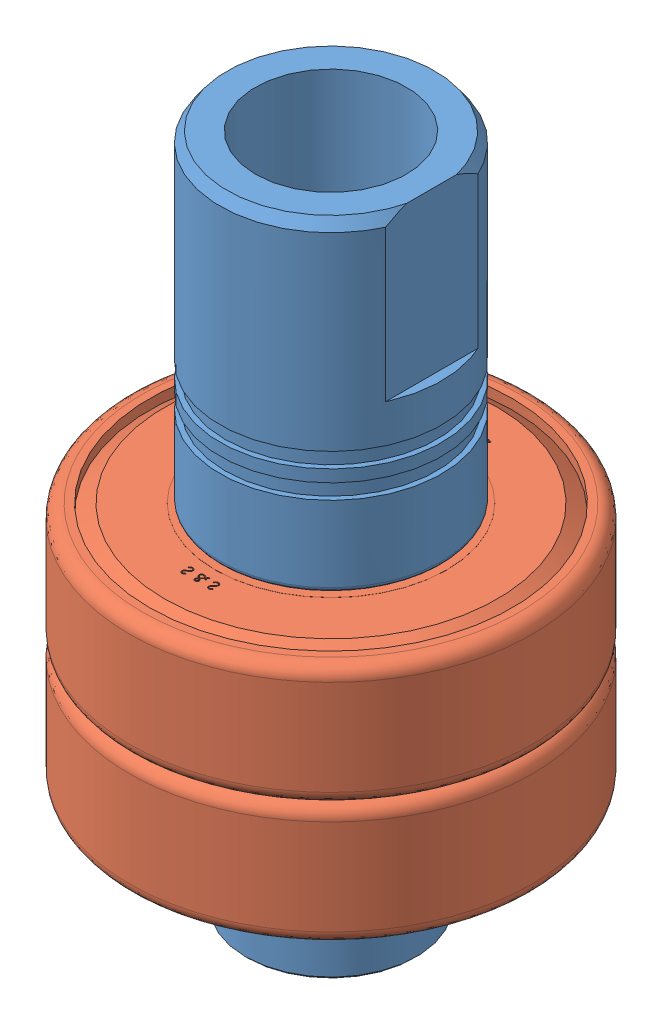
SolidWorks assembly Part5, configuration Default. Lengths in mm.
Overall size (54.35 67 54.35).
3 component instances, 2 part files, 4 mates.
Components (placement in the parent):
- Part5I-1: Part5I [Default] at (-13.2455 -26.8007 2.4381) size (22 67 22)
- Part5II-1: Part5II [Default] at (-13.2455 -3.8107 2.4381) size (40 12.01 40)
- Part5II-2: Part5II [Default] at (-13.2455 -3.8107 2.4381) x (0.483218 0 0.8755) z (0.8755 0 -0.483218) size (40 12.01 40)
Mates (geometry in assembly coordinates):
- Coincident1: coincident anti-aligned: plane of Part5If-1 through (-13.2455 8.1993 2.4381) normal (0 -1 0); plane of Part5IIF-1 through (-13.2455 8.1993 2.4381) normal (0 1 0)
- Concentric1: concentric anti-aligned: cylinder of Part5IIF-1 through (-13.2455 8.1893 2.4381) axis (0 -1 0) radius 8.5; cylinder of Part5IIF-2 through (-13.2455 -15.8107 2.4381) axis (0 1 0) radius 8.5
- Concentric2: concentric aligned: cylinder of Part5If-1 through (-13.2455 8.1993 2.4381) axis (0 -1 0) radius 8.5; cylinder of Part5IIF-1 through (-13.2455 8.1893 2.4381) axis (0 -1 0) radius 8.5
- Coincident2: coincident anti-aligned: plane of Part5IIF-1 through (-13.2455 -3.8107 2.4381) normal (0 -1 0); plane of Part5IIF-2 through (-13.2455 -3.8107 2.4381) normal (0 1 0)
